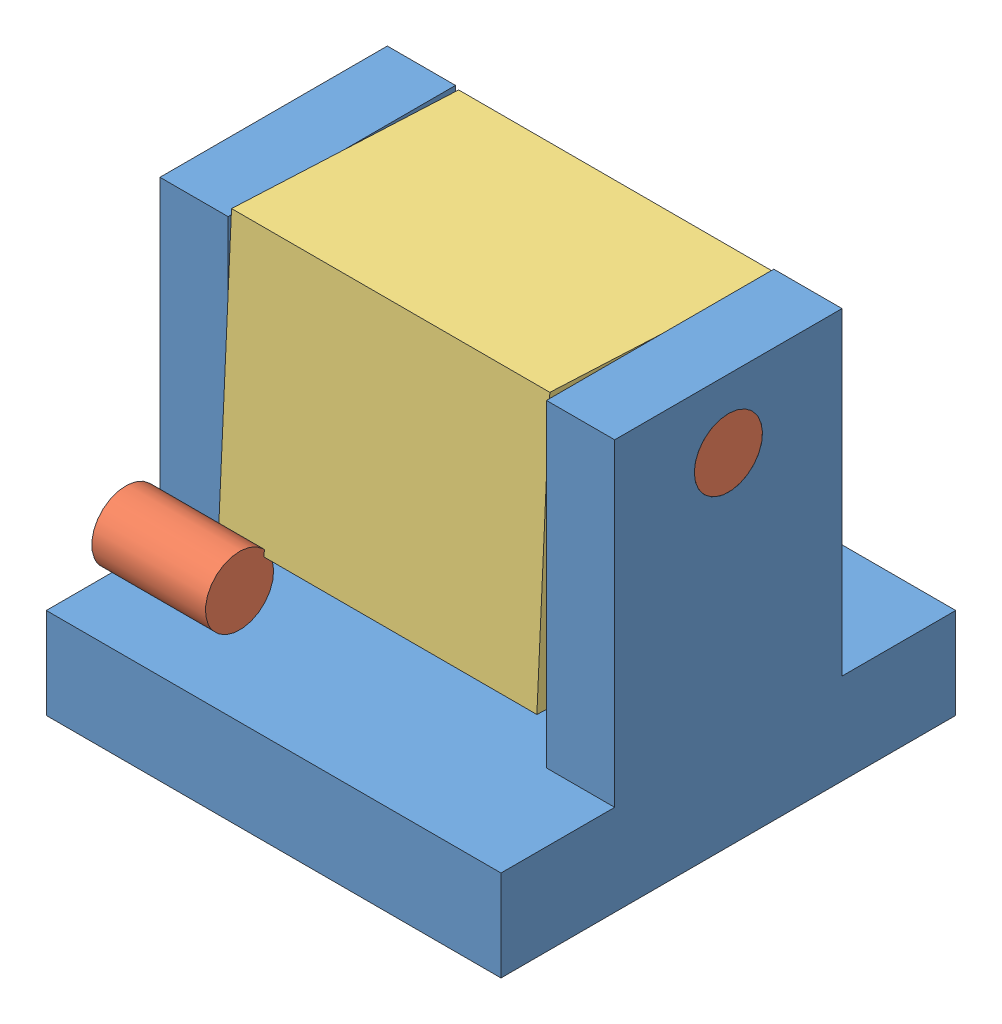
SolidWorks assembly Assem1, configuration 默认. Lengths in mm.
Overall size (50 45.59 50).
5 component instances, 3 part files, 10 mates.
Components (placement in the parent):
- U-bracket-1: U-bracket [默认] at (-18.3734 6.8097 74.4944) size (50 45 50)
- pin-1: pin [Default] at (31.6266 44.3097 49.4944) x (-1 0 0) z (0 -0.798806 0.601589) size (12.5 7.5 7.5)
- pin-2: pin [Default] at (-18.3734 44.3097 49.4944) x (1 0 0) z (0 -0.03925 -0.999229) size (12.5 7.5 7.5)
- block-1: block [默认] at (-10.8734 22.4292 63.0497) x (1 0 0) z (0 0.047527 0.99887) size (35 30 25)
- pin-3: pin [Default] at (-18.3734 20.5597 65.7444) x (1 0 0) z (0 0.509438 -0.860507) size (12.5 7.5 7.5)
Mates (geometry in assembly coordinates):
- Coincident2: coincident anti-aligned: plane of pin-1 through (19.1266 44.3097 49.4944) normal (-1 0 0); plane of block-1 through (19.1266 44.3097 49.4944) normal (1 0 0)
- Concentric1: concentric anti-aligned: circle of pin-1; circle of block-1
- Coincident6: coincident anti-aligned: plane of pin-2 through (-5.8734 44.3097 49.4944) normal (1 0 0); plane of block-1 through (-5.8734 44.3097 49.4944) normal (-1 0 0)
- Concentric2: concentric anti-aligned: circle of pin-2; circle of block-1
- Coincident9: coincident aligned: plane of U-bracket-1 through (31.6266 16.8097 74.4944) normal (1 0 0); plane of pin-1 through (31.6266 44.3097 49.4944) normal (1 0 0)
- Concentric3: concentric aligned: cylinder of U-bracket-1 through (-28.98 44.3097 49.4944) axis (1 0 0) radius 3.75; cylinder of pin-1 through (19.1266 44.3097 49.4944) axis (1 0 0) radius 3.75
- Parallel3: parallel aligned: plane of U-bracket-1 through (-18.3734 51.8097 74.4944) normal (0 1 0); plane of block-1
- Tangent2: tangent anti-aligned: plane of U-bracket-1 through (-18.3734 51.8097 61.9944) normal (0 0 1); cylinder of pin-3 through (-5.8734 20.5597 65.7444) axis (-1 0 0) radius 3.75
- Tangent3: tangent anti-aligned: plane of U-bracket-1 through (-18.3734 16.8097 74.4944) normal (0 1 0); cylinder of pin-3 through (-5.8734 20.5597 65.7444) axis (-1 0 0) radius 3.75
- Coincident13: coincident aligned: plane of U-bracket-1 through (-18.3734 16.8097 74.4944) normal (-1 0 0); plane of pin-3 through (-18.3734 20.5597 65.7444) normal (-1 0 0)
